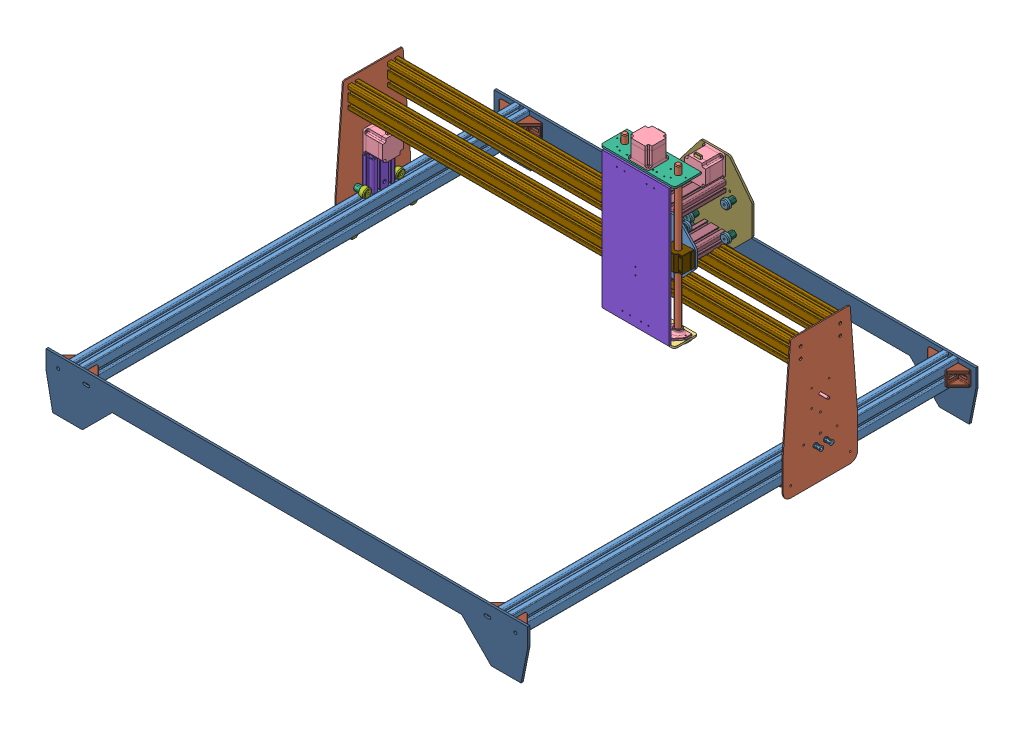
SolidWorks assembly ensamble eje x, configuration Predeterminado. Lengths in mm.
Overall size (1296.37 722.23 1212).
91 component instances, 26 part files, 78 mates.
Components (placement in the parent):
- perfil120_v1-1: perfil120_v1 [Predeterminado] at (-8.6844 -3.846 600) size (40 60 1200)
- soporteEjeX-1: soporteEjeX [Predeterminado] at (14.9148 134.7717 976.7609) x (0 0 -1) z (1 0 0) size (200 370 3)
- MotorStepper-1: MotorStepper [Predeterminado] at (-12.2202 160.9824 977.1474) x (0 0 1) z (-1 0 0) size (56.4 63.4 77.3)
  - JST XH 6 S6B-XH-A1 shrouded header connector-3: JST XH 6 S6B-XH-A1 shrouded header connector [Default] at (-0.3865 1.9892 17.54) size (17.54 10.45 5.75)
  - tapa-3: tapa [Predeterminado] at (-0.3865 -26.2108 -27.135) size (56.4 56.4 77.3)
- poleaLoca_prueba-1: poleaLoca_prueba [Predeterminado] at (25.4148 21.0717 962.7609) x (0 0 -1) z (-1 0 0) size (12 12 17)
- poleaLoca_prueba-2: poleaLoca_prueba [Predeterminado] at (25.4148 21.0717 990.7609) x (0 0 -1) z (-1 0 0) size (12 12 17)
- espaciador-1: espaciador [Predeterminado] at (0.1148 36.3717 931.7609) x (0 0 -1) z (1 0 0) size (16.39 15.04 14.8)
- espaciador-2: espaciador [Predeterminado] at (0.1148 36.3717 1021.7609) x (0 0 -1) z (1 0 0) size (16.39 15.04 14.8)
- espaciador-3: espaciador [Predeterminado] at (0.1148 -40.7283 1056.7609) x (0 0 -1) z (1 0 0) size (16.39 15.04 14.8)
- espaciador-4: espaciador [Predeterminado] at (0.1148 -40.7283 896.7609) x (0 0 -1) z (1 0 0) size (16.39 15.04 14.8)
- rueda solida tipo v-6: rueda solida tipo v [Predeterminado] at (-7.8852 36.3717 1021.7609) size (16.1 24 24)
- rueda solida tipo v-7: rueda solida tipo v [Predeterminado] at (-7.8852 36.3717 931.7609) size (16.1 24 24)
- rueda solida tipo v-8: rueda solida tipo v [Predeterminado] at (-7.8852 -40.7283 896.7609) size (16.1 24 24)
- rueda solida tipo v-9: rueda solida tipo v [Predeterminado] at (-7.8852 -40.7283 1056.7609) size (16.1 24 24)
- perfil_soporte_motor-1: perfil_soporte_motor [Predeterminado] at (-0.1352 106.5717 976.4609) x (1 0 0) z (0 -1 0) size (30.1 60.1 80)
- perfil120_v2-2: perfil120_v2 [Predeterminado] at (-1185.0852 256.5717 923.5109) x (0 0 -1) z (1 0 0) size (30.1 60.1 1200)
- perfil120_v2-3: perfil120_v2 [Predeterminado] at (-1185.0852 256.5717 1030.0109) x (0 0 -1) z (1 0 0) size (30.1 60.1 1200)
- soporteEjeX-2: soporteEjeX [Predeterminado] at (-1185.0852 134.7717 976.7609) x (0 0 1) z (-1 0 0) size (200 370 3)
- MotorStepper-2: MotorStepper [Predeterminado] at (-1157.9502 160.9824 976.3745) x (0 0 -1) z (1 0 0) size (56.4 63.4 77.3)
  - JST XH 6 S6B-XH-A1 shrouded header connector-3: JST XH 6 S6B-XH-A1 shrouded header connector [Default] at (-0.3865 1.9892 17.54) size (17.54 10.45 5.75)
  - tapa-3: tapa [Predeterminado] at (-0.3865 -26.2108 -27.135) size (56.4 56.4 77.3)
- poleaLoca_prueba-3: poleaLoca_prueba [Predeterminado] at (-1195.5852 21.0717 990.7609) x (0 0.924225 0.381849) z (1 0 0) size (12 12 17)
- poleaLoca_prueba-4: poleaLoca_prueba [Predeterminado] at (-1195.5852 21.0717 962.7609) x (0 0.924225 0.381849) z (1 0 0) size (12 12 17)
- espaciador-5: espaciador [Predeterminado] at (-1170.2852 36.3717 1021.7609) x (0 -0.924225 -0.381849) z (-1 0 0) size (16.39 15.04 14.8)
- espaciador-6: espaciador [Predeterminado] at (-1170.2852 36.3717 931.7609) x (0 -0.924225 -0.381849) z (-1 0 0) size (16.39 15.04 14.8)
- espaciador-7: espaciador [Predeterminado] at (-1170.2852 -40.7283 896.7609) x (0 -0.924225 -0.381849) z (-1 0 0) size (16.39 15.04 14.8)
- espaciador-8: espaciador [Predeterminado] at (-1170.2852 -40.7283 1056.7609) x (0 -0.924225 -0.381849) z (-1 0 0) size (16.39 15.04 14.8)
- rueda solida tipo v-10: rueda solida tipo v [Predeterminado] at (-1162.2852 36.3717 931.7609) x (-1 0 0) z (0 0.924225 0.381849) size (16.1 24 24)
- rueda solida tipo v-11: rueda solida tipo v [Predeterminado] at (-1162.2852 36.3717 1021.7609) x (-1 0 0) z (0 -0.924225 -0.381849) size (16.1 24 24)
- rueda solida tipo v-12: rueda solida tipo v [Predeterminado] at (-1162.2852 -40.7283 1056.7609) x (-1 0 0) z (0 0.924225 0.381849) size (16.1 24 24)
- rueda solida tipo v-13: rueda solida tipo v [Predeterminado] at (-1162.2852 -40.7283 896.7609) x (-1 0 0) z (0 0.924225 0.381849) size (16.1 24 24)
- perfil_soporte_motor-2: perfil_soporte_motor [Predeterminado] at (-1170.0352 106.5717 977.0609) x (-1 0 0) z (0 -1 0) size (30.1 60.1 80)
- perfil120_v1-2: perfil120_v1 [Predeterminado] at (-1162.1914 -3.846 1800) x (-1 0 0) z (0 0 -1) size (40 60 1200)
- patas base-1: patas base [Predeterminado] at (-588.4391 -3.846 1800) size (1296 140 6)
- patas base-2: patas base [Predeterminado] at (-588.8131 -3.846 594) size (1296 140 6)
- escuadra-1: escuadra [Predeterminado] at (-1200.1914 -3.3924 618) x (-1 0 0) z (0 -1 0) size (36 36 38.2)
- escuadra-2: escuadra [Predeterminado] at (-1124.1914 -2.8452 1782) x (1 0 0) z (0 -1 0) size (36 36 38.2)
- escuadra-3: escuadra [Predeterminado] at (29.3156 -2.9149 1782) x (1 0 0) z (0 -1 0) size (36 36 38.2)
- escuadra-4: escuadra [Predeterminado] at (-46.6844 -4.16 618) x (-1 0 0) z (0 -1 0) size (36 36 38.2)
- escuadra-6: escuadra [Predeterminado] at (-46.6844 -3.5917 1782) x (-1 0 0) z (0 1 0) size (36 36 38.2)
- escuadra-7: escuadra [Predeterminado] at (29.3156 -3.8061 618) x (1 0 0) z (0 1 0) size (36 36 38.2)
- escuadra-8: escuadra [Predeterminado] at (-1200.1914 -3.03 1782) x (-1 0 0) z (0 1 0) size (36 36 38.2)
- escuadra-9: escuadra [Predeterminado] at (-1124.1914 -3.8998 618) x (1 0 0) z (0 1 0) size (36 36 38.2)
- ensamble eje y-1: ensamble eje y [Predeterminado] at (-337.6078 363.1242 700.7265) size (243.17 437.77 292.91)
  - carrto eje y-1: carrto eje y [Predeterminado] at (-101.8622 -12.3734 164.056) x (0 0 -1) z (1 0 0) size (5 210.1 200)
  - perfilCarritoEjeY-1: perfilCarritoEjeY [Predeterminado] at (-1.9122 -66.2624 202.5) x (-0.000838 -1 0) z (0 0 1) size (30.1 60.1 146.6)
  - perfilCarritoEjeY-2: perfilCarritoEjeY [Predeterminado] at (-1.9122 52.8254 202.5) x (0 -1 0) z (0 0 1) size (30.1 60.1 146.6)
  - rueda solida tipo v unit-1: rueda solida tipo v unit [Predeterminado] at (49.2925 -43.7081 293.8935) x (0 0 -1) z (0.999888 0.014988 0) size (10.2 24 24)
  - rueda solida tipo v unit-2: rueda solida tipo v unit [Predeterminado] at (-79.2013 -38.7028 293.8935) x (0 0 -1) z (0.93492 -0.35486 0) size (10.2 24 24)
  - rueda solida tipo v unit-3: rueda solida tipo v unit [Predeterminado] at (52.1991 -123.7096 293.8935) x (0 0 -1) z (0.99861 0.052715 0) size (10.2 24 24)
  - rueda solida tipo v unit-4: rueda solida tipo v unit [Predeterminado] at (-67.6119 28.6405 293.8935) x (0 0 -1) z (-0.978881 -0.20443 0) size (10.2 24 24)
  - rueda solida tipo v unit-5: rueda solida tipo v unit [Predeterminado] at (-25.5941 -39.0402 400.2935) x (0 0 -1) z (0.940002 0.34117 0) size (10.2 24 24)
  - rueda solida tipo v unit-6: rueda solida tipo v unit [Predeterminado] at (48.0542 -123.8465 400.2935) x (0 0 -1) z (1 0 0) size (10.2 24 24)
  - rueda solida tipo v unit-7: rueda solida tipo v unit [Predeterminado] at (45.801 -43.7116 400.2935) x (0 0 -1) z (0.999546 -0.030118 0) size (10.2 24 24)
  - rueda solida tipo v unit-8: rueda solida tipo v unit [Predeterminado] at (-51.9458 -123.7625 400.2935) x (0 0 -1) z (1 0 0) size (10.2 24 24)
  - separadorEjeY-1: separadorEjeY [Predeterminado] at (48.0542 -46.8044 334.1) size (16.39 15.04 15)
  - separadorEjeY-2: separadorEjeY [Predeterminado] at (48.1214 33.2956 334.1) x (0.930818 -0.365482 0) z (0 0 1) size (16.39 15.04 15)
  - separadorEjeY-3: separadorEjeY [Predeterminado] at (-51.9458 -46.7204 334.1) size (16.39 15.04 15)
  - separadorEjeY-4: separadorEjeY [Predeterminado] at (-51.8785 33.3796 334.1) x (1 0.000043 0) z (0 0 1) size (16.39 15.04 15)
  - separadorEjeY-5: separadorEjeY [Predeterminado] at (48.1378 33.3254 202.5) size (16.39 15.04 15)
  - separadorEjeY-6: separadorEjeY [Predeterminado] at (-51.8622 -46.7746 202.5) size (16.39 15.04 15)
  - separadorEjeY-7: separadorEjeY [Predeterminado] at (48.1378 -46.7746 202.5) x (0.972112 0.234517 0) z (0 0 1) size (16.39 15.04 15)
  - separadorEjeY-8: separadorEjeY [Predeterminado] at (-51.8622 33.3254 202.5) size (16.39 15.04 15)
  - MotorStepper-1: MotorStepper [Predeterminado] at (-1.4757 126.3362 229.635) size (56.4 63.4 77.3)
    - JST XH 6 S6B-XH-A1 shrouded header connector-3: JST XH 6 S6B-XH-A1 shrouded header connector [Default] at (-0.3865 1.9892 17.54) size (17.54 10.45 5.75)
    - tapa-3: tapa [Predeterminado] at (-0.3865 -26.2108 -27.135) size (56.4 56.4 77.3)
  - ensamble eje z-1: ensamble eje z [Predeterminado] at (-342.631 35.1306 285.2346) x (0.00084 1 0) z (0.951153 -0.000799 0.30872) size (437.57 131.9 212.46)
    - SinFin-1: SinFin [Predeterminado] at (133.0173 -25.4285 350) size (350 10.12 10.12)
    - camisa8mm-1: camisa8mm [Predeterminado] at (-56.5569 -25.4285 350) x (0 -0.30872 0.951153) z (1 0 0) size (30 30 30)
    - camisaBaleroLineal-1: camisaBaleroLineal [Predeterminado] at (-63.5569 0.8417 282.829) x (0 -0.30872 0.951153) z (1 0 0) size (50 38.5 44)
    - camisaBaleroLineal-2: camisaBaleroLineal [Predeterminado] at (-63.5569 -43.6139 419.7951) x (0 -0.30872 0.951153) z (1 0 0) size (50 38.5 44)
    - carrito eje y 2-5: carrito eje y 2 [Predeterminado] at (-47.2058 -13.5796 248.7103) x (0 -0.30872 0.951153) z (0 0.951153 0.30872) size (200 150.1 5)
    - varillaLisa-1: varillaLisa [Predeterminado] at (-222.2482 0.8417 282.829) x (0 0.757979 -0.652279) z (1 0 0) size (15 15 400)
    - varillaLisa-2: varillaLisa [Predeterminado] at (-222.2482 -43.6139 419.7951) x (0 0.785648 -0.618673) z (1 0 0) size (15 15 400)
    - baseRieles-1: baseRieles [Predeterminado] at (-222.2482 -39.6958 345.3692) x (0 -0.30872 0.951153) z (1 0 0) size (200 62 5)
    - acopleVarillaLisa-2: acopleVarillaLisa [Predeterminado] at (-217.2482 0.8417 282.829) x (0 -0.30872 0.951153) z (1 0 0) size (51.4 39.01 15)
    - acopleVarillaLisa-3: acopleVarillaLisa [Predeterminado] at (-217.2482 -43.6139 419.7951) x (0 -0.30872 0.951153) z (1 0 0) size (51.4 39.01 15)
    - acopleVarillaLisa2-3: acopleVarillaLisa2 [Predeterminado] at (-222.2482 0.8417 282.829) x (0 0.30872 -0.951153) z (-1 0 0) size (51.4 38.55 5)
    - acopleVarillaLisa2-4: acopleVarillaLisa2 [Predeterminado] at (-222.2482 -43.6139 419.7951) x (0 0.30872 -0.951153) z (-1 0 0) size (51.4 38.55 5)
    - baseRielesMotor-1: baseRielesMotor [Predeterminado] at (150.4173 -39.3685 343.3007) x (0 -0.30872 0.951153) z (1 0 0) size (200 72 5)
    - MotorStepper-1: MotorStepper [Predeterminado] at (184.1523 -39.0644 345.9804) x (0 -0.30872 0.951153) z (1 0 0) size (56.4 63.4 77.3)
      - JST XH 6 S6B-XH-A1 shrouded header connector-3: JST XH 6 S6B-XH-A1 shrouded header connector [Default] at (-0.3865 1.9892 17.54) size (17.54 10.45 5.75)
      - tapa-3: tapa [Predeterminado] at (-0.3865 -26.2108 -27.135) size (56.4 56.4 77.3)
    - LPlacaBaseRiel-1: LPlacaBaseRiel [Predeterminado] at (125.4173 20.5693 328.1323) x (1 0 0) z (0 0.30872 -0.951153) size (25 25 30)
    - LPlacaBaseRiel-2: LPlacaBaseRiel [Predeterminado] at (125.4173 -10.3026 423.2476) x (1 0 0) z (0 0.30872 -0.951153) size (25 25 30)
    - LPlacaBaseRiel-3: LPlacaBaseRiel [Predeterminado] at (-192.2482 6.677 370.9342) x (-1 0 0) z (0 -0.30872 0.951153) size (25 25 30)
    - LPlacaBaseRiel-4: LPlacaBaseRiel [Predeterminado] at (-192.2482 22.1129 323.3765) x (-1 0 0) z (0 -0.30872 0.951153) size (25 25 30)
    - placa-1: placa [Predeterminado] at (-33.2482 19.2757 364.5098) x (0 0.30872 -0.951153) z (0 -0.951153 -0.30872) size (180 368 5)
  - poleaLoca_prueba-3: poleaLoca_prueba [Predeterminado] at (38.1378 46.9254 190.05) size (12 12 17)
  - poleaLoca_prueba-4: poleaLoca_prueba [Predeterminado] at (-41.8622 46.9254 190.05) size (12 12 17)
Mates (geometry in assembly coordinates):
- Coincidente12: coincident anti-aligned: circle of soporteEjeX-1; circle of poleaLoca_prueba-2
- Coincidente13: coincident anti-aligned: circle of soporteEjeX-1; circle of poleaLoca_prueba-1
- Concéntrica12: concentric aligned: circle of soporteEjeX-1; circle of espaciador-2
- Concéntrica13: concentric aligned: circle of soporteEjeX-1; circle of espaciador-1
- Concéntrica15: concentric aligned: circle of espaciador-1; circle of rueda solida tipo v-7
- Concéntrica16: concentric aligned: circle of espaciador-2; circle of rueda solida tipo v-6
- Concéntrica17: concentric aligned: circle of soporteEjeX-1; circle of espaciador-3
- Concéntrica18: concentric aligned: circle of espaciador-3; circle of rueda solida tipo v-9
- Concéntrica19: concentric aligned: circle of soporteEjeX-1; circle of espaciador-4
- Concéntrica20: concentric aligned: circle of espaciador-4; circle of rueda solida tipo v-8
- Paralelo3: parallel anti-aligned: plane of perfil120_v1-1 through (11.3156 1.369 1800) normal (1 0 0); plane of soporteEjeX-1 through (14.9148 134.7717 976.7609) normal (-1 0 0)
- Coincidente15: coincident anti-aligned: circle of soporteEjeX-1; circle of MotorStepper-1/tapa-3
- Coincidente16: coincident anti-aligned: circle of soporteEjeX-1; circle of MotorStepper-1/tapa-3
- Paralelo4: parallel aligned: line of perfil120_v1-1 through (11.3156 -31.846 1800) axis (0 0 -1); line of soporteEjeX-1 through (14.9148 -69.4283 1056.7609) axis (0 0 -1)
- Coincidente18: coincident anti-aligned: plane of soporteEjeX-1 through (14.9148 134.7717 976.7609) normal (-1 0 0); plane of espaciador-1 through (14.9148 40.8494 934.3971) normal (1 0 0)
- Coincidente19: coincident anti-aligned: plane of soporteEjeX-1 through (14.9148 134.7717 976.7609) normal (-1 0 0); plane of espaciador-2 through (14.9148 40.8494 1024.3971) normal (1 0 0)
- Coincidente20: coincident anti-aligned: plane of soporteEjeX-1 through (14.9148 134.7717 976.7609) normal (-1 0 0); plane of espaciador-3 through (14.9148 -36.2506 1059.3971) normal (1 0 0)
- Coincidente21: coincident anti-aligned: plane of soporteEjeX-1 through (14.9148 134.7717 976.7609) normal (-1 0 0); plane of espaciador-4 through (14.9148 -36.2506 899.3971) normal (1 0 0)
- Coincidente22: coincident anti-aligned: plane of espaciador-4 through (0.1148 -36.2506 899.3971) normal (-1 0 0); plane of rueda solida tipo v-8 through (0.1148 -40.7283 896.7609) normal (1 0 0)
- Coincidente23: coincident anti-aligned: plane of espaciador-3 through (0.1148 -36.2506 1059.3971) normal (-1 0 0); plane of rueda solida tipo v-9 through (0.1148 -40.7283 1056.7609) normal (1 0 0)
- Coincidente24: coincident anti-aligned: plane of espaciador-1 through (0.1148 40.8494 934.3971) normal (-1 0 0); circle of rueda solida tipo v-7
- Coincidente25: coincident anti-aligned: plane of espaciador-2 through (0.1148 40.8494 1024.3971) normal (-1 0 0); plane of rueda solida tipo v-6 through (0.1148 36.3717 1021.7609) normal (1 0 0)
- Concéntrica21: concentric aligned: circle of soporteEjeX-1; circle of perfil_soporte_motor-1
- Concéntrica22: concentric aligned: circle of soporteEjeX-1; circle of perfil_soporte_motor-1
- Concéntrica24: concentric anti-aligned: circle of soporteEjeX-1; circle of perfil120_v2-2
- Coincidente28: coincident anti-aligned: plane of soporteEjeX-1 through (14.9148 134.7717 976.7609) normal (-1 0 0); plane of perfil120_v2-2 through (14.9148 256.5717 923.5109) normal (1 0 0)
- Concéntrica25: concentric aligned: circle of soporteEjeX-1; circle of perfil120_v2-3
- Coincidente29: coincident anti-aligned: plane of soporteEjeX-1 through (14.9148 134.7717 976.7609) normal (-1 0 0); plane of perfil120_v2-3 through (14.9148 256.5717 1030.0109) normal (1 0 0)
- Concéntrica26: concentric aligned: circle of soporteEjeX-2; circle of perfil_soporte_motor-2
- Concéntrica27: concentric aligned: circle of soporteEjeX-2; circle of perfil_soporte_motor-2
- Coincidente30: coincident anti-aligned: circle of soporteEjeX-2; circle of MotorStepper-2/tapa-3
- Coincidente31: coincident anti-aligned: plane of soporteEjeX-2 through (-1185.0852 134.7717 976.7609) normal (1 0 0); plane of espaciador-5 through (-1185.0852 37.0983 1026.906) normal (-1 0 0)
- Coincidente32: coincident anti-aligned: plane of soporteEjeX-2 through (-1185.0852 134.7717 976.7609) normal (1 0 0); plane of espaciador-7 through (-1185.0852 -40.0017 901.906) normal (-1 0 0)
- Concéntrica28: concentric aligned: circle of soporteEjeX-2; circle of espaciador-5
- Concéntrica29: concentric aligned: circle of espaciador-5; circle of rueda solida tipo v-11
- Concéntrica30: concentric aligned: circle of soporteEjeX-2; circle of espaciador-7
- Coincidente33: coincident anti-aligned: circle of soporteEjeX-2; circle of MotorStepper-2/tapa-3
- Concéntrica31: concentric aligned: circle of espaciador-6; circle of rueda solida tipo v-10
- Concéntrica32: concentric aligned: circle of espaciador-8; circle of rueda solida tipo v-12
- Concéntrica33: concentric aligned: circle of soporteEjeX-2; circle of espaciador-6
- Concéntrica34: concentric aligned: circle of soporteEjeX-2; circle of espaciador-8
- Coincidente34: coincident anti-aligned: circle of soporteEjeX-2; circle of poleaLoca_prueba-4
- Paralelo7: parallel anti-aligned: plane of soporteEjeX-2 through (-1185.0852 134.7717 976.7609) normal (1 0 0); plane of perfil120_v1-2 through (-1182.1914 1.369 600) normal (-1 0 0)
- Coincidente35: coincident anti-aligned: circle of soporteEjeX-2; circle of poleaLoca_prueba-3
- Concéntrica35: concentric aligned: circle of espaciador-7; circle of rueda solida tipo v-13
- Paralelo8: parallel aligned: line of soporteEjeX-2 through (-1185.0852 -69.4283 896.7609) axis (0 0 1); line of perfil120_v1-2 through (-1182.1914 -31.846 600) axis (0 0 1)
- Coincidente36: coincident anti-aligned: plane of soporteEjeX-2 through (-1185.0852 134.7717 976.7609) normal (1 0 0); plane of espaciador-6 through (-1185.0852 37.0983 936.906) normal (-1 0 0)
- Coincidente37: coincident anti-aligned: plane of soporteEjeX-2 through (-1185.0852 134.7717 976.7609) normal (1 0 0); plane of espaciador-8 through (-1185.0852 -40.0017 1061.906) normal (-1 0 0)
- Coincidente38: coincident anti-aligned: plane of espaciador-8 through (-1170.2852 -40.0017 1061.906) normal (1 0 0); plane of rueda solida tipo v-12 through (-1170.2852 -40.7283 1056.7609) normal (-1 0 0)
- Coincidente39: coincident anti-aligned: plane of espaciador-5 through (-1170.2852 37.0983 1026.906) normal (1 0 0); circle of rueda solida tipo v-11
- Coincidente40: coincident anti-aligned: plane of espaciador-7 through (-1170.2852 -40.0017 901.906) normal (1 0 0); plane of rueda solida tipo v-13 through (-1170.2852 -40.7283 896.7609) normal (-1 0 0)
- Coincidente41: coincident anti-aligned: plane of espaciador-6 through (-1170.2852 37.0983 936.906) normal (1 0 0); plane of rueda solida tipo v-10 through (-1170.2852 36.3717 931.7609) normal (-1 0 0)
- Concéntrica37: concentric anti-aligned: circle of perfil120_v2-3; circle of soporteEjeX-2
- Concéntrica38: concentric aligned: circle of perfil120_v2-2; circle of soporteEjeX-2
- Coincidente43: coincident anti-aligned: plane of perfil120_v2-2 through (-1185.0852 256.5717 923.5109) normal (-1 0 0); plane of soporteEjeX-2 through (-1185.0852 134.7717 976.7609) normal (1 0 0)
- Coincidente45: coincident anti-aligned: plane of soporteEjeX-2 through (-1185.0852 134.7717 976.7609) normal (1 0 0); plane of perfil_soporte_motor-2 through (-1185.0852 26.5717 977.0609) normal (-1 0 0)
- Coincidente46: coincident anti-aligned: plane of soporteEjeX-1 through (14.9148 134.7717 976.7609) normal (-1 0 0); plane of perfil_soporte_motor-1 through (14.9148 26.5717 976.4609) normal (1 0 0)
- Coincidente48: coincident anti-aligned: plane of perfil120_v1-1 through (-28.6844 1.369 1800) normal (-1 0 0); plane of escuadra-6 through (-28.6844 -22.6917 1782) normal (1 0 0)
- Coincidente49: coincident anti-aligned: plane of patas base-1 through (-588.4391 -3.846 1800) normal (0 0 -1); plane of escuadra-6 through (-46.6844 -22.6917 1800) normal (0 0 1)
- Coincidente50: coincident anti-aligned: plane of patas base-1 through (-588.4391 -3.846 1800) normal (0 0 -1); plane of escuadra-8 through (-1200.1914 -22.13 1800) normal (0 0 1)
- Coincidente51: coincident anti-aligned: plane of perfil120_v1-2 through (-1182.1914 1.369 600) normal (-1 0 0); plane of escuadra-8 through (-1182.1914 -22.13 1782) normal (1 0 0)
- Coincidente52: coincident anti-aligned: plane of perfil120_v1-2 through (-1162.1914 -3.846 1800) normal (0 0 1); plane of patas base-1 through (-588.4391 -3.846 1800) normal (0 0 -1)
- Coincidente54: coincident aligned: line of perfil120_v1-1 through (9.3156 26.154 1800) axis (-1 0 0); line of patas base-1 through (59.5609 26.154 1800) axis (-1 0 0)
- Coincidente55: coincident anti-aligned: line of perfil120_v1-2 through (-1180.1914 26.154 1800) axis (1 0 0); line of patas base-1 through (59.5609 26.154 1800) axis (-1 0 0)
- Coincidente56: coincident aligned: line of perfil120_v1-1 through (-16.8844 26.154 600) axis (-1 0 0); line of patas base-2 through (59.1869 26.154 600) axis (-1 0 0)
- Coincidente57: coincident anti-aligned: plane of patas base-1 through (-588.4391 -3.846 1800) normal (0 0 -1); plane of escuadra-2 through (-1124.1914 16.2548 1800) normal (0 0 1)
- Coincidente58: coincident anti-aligned: plane of perfil120_v1-2 through (-1142.1914 1.369 600) normal (1 0 0); plane of escuadra-2 through (-1142.1914 16.2548 1782) normal (-1 0 0)
- Coincidente59: coincident anti-aligned: plane of patas base-1 through (-588.4391 -3.846 1800) normal (0 0 -1); plane of escuadra-3 through (29.3156 16.1851 1800) normal (0 0 1)
- Coincidente60: coincident anti-aligned: plane of perfil120_v1-1 through (11.3156 1.369 1800) normal (1 0 0); plane of escuadra-3 through (11.3156 16.1851 1782) normal (-1 0 0)
- Coincidente61: coincident anti-aligned: plane of perfil120_v1-1 through (-8.6844 -3.846 600) normal (0 0 -1); plane of patas base-2 through (-588.8131 -3.846 600) normal (0 0 1)
- Coincidente62: coincident anti-aligned: plane of perfil120_v1-2 through (-1142.1914 -33.846 600) normal (1 0 0); plane of escuadra-9 through (-1142.1914 -22.9998 618) normal (-1 0 0)
- Coincidente63: coincident anti-aligned: plane of patas base-2 through (-588.8131 -3.846 600) normal (0 0 1); plane of escuadra-9 through (-1124.1914 -22.9998 600) normal (0 0 -1)
- Coincidente64: coincident anti-aligned: plane of perfil120_v1-2 through (-1182.1914 1.369 600) normal (-1 0 0); plane of escuadra-1 through (-1182.1914 15.7076 618) normal (1 0 0)
- Coincidente65: coincident anti-aligned: plane of patas base-2 through (-588.8131 -3.846 600) normal (0 0 1); plane of escuadra-1 through (-1200.1914 15.7076 600) normal (0 0 -1)
- Coincidente66: coincident anti-aligned: plane of patas base-2 through (-588.8131 -3.846 600) normal (0 0 1); plane of escuadra-7 through (29.3156 -22.9061 600) normal (0 0 -1)
- Coincidente67: coincident anti-aligned: plane of perfil120_v1-1 through (11.3156 1.369 1800) normal (1 0 0); plane of escuadra-7 through (11.3156 -22.9061 618) normal (-1 0 0)
- Coincidente68: coincident anti-aligned: plane of perfil120_v1-1 through (-28.6844 -33.846 1800) normal (-1 0 0); plane of escuadra-4 through (-28.6844 14.94 618) normal (1 0 0)
- Coincidente69: coincident anti-aligned: plane of patas base-2 through (-588.8131 -3.846 600) normal (0 0 1); plane of escuadra-4 through (-46.6844 14.94 600) normal (0 0 -1)
